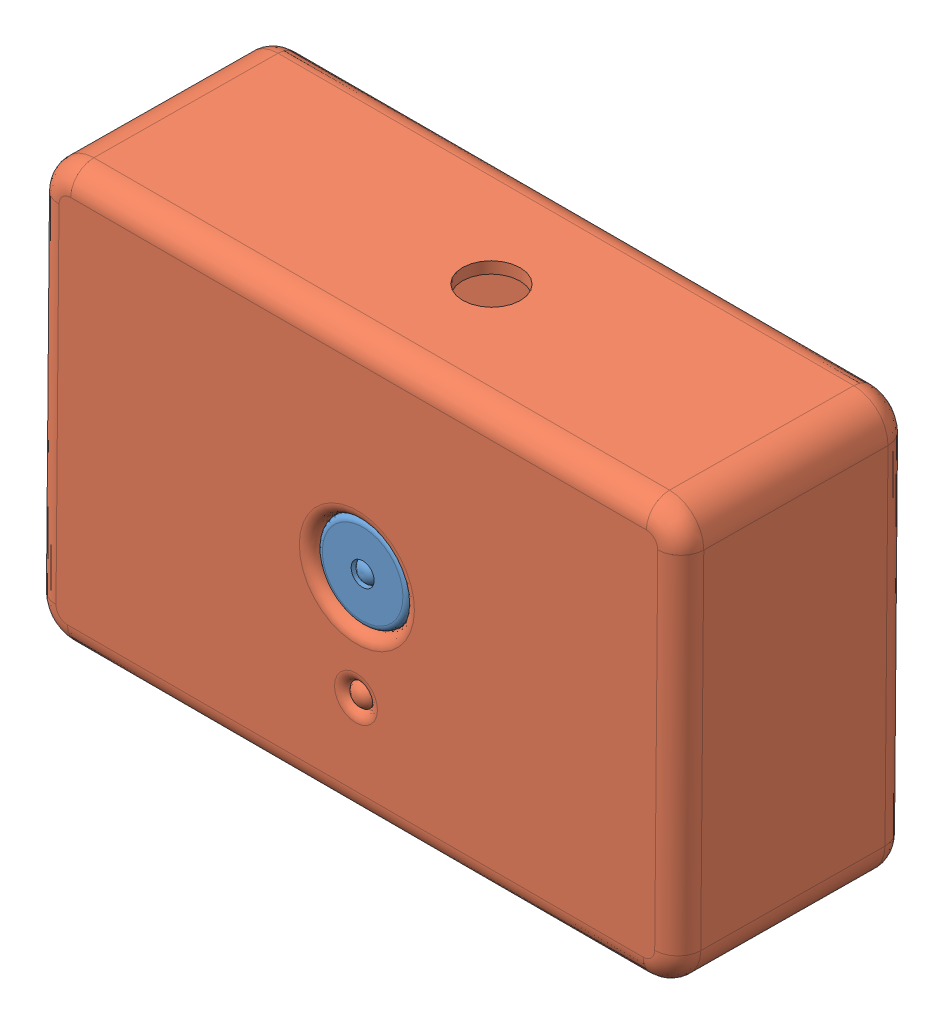
SolidWorks assembly Camara, configuration Predeterminado. Lengths in mm.
Overall size (56 36.17 20.31).
2 component instances, 2 part files, 1 mates.
Components (placement in the parent):
- Camara-1: Camara [Predeterminado] at (-38.4113 -4.107 68.8002) x (1 0 0) z (0 -0.999962 0.008727) size (30 3.56 30)
- GoProCamara-1: GoProCamara [Predeterminado] at (-38.4113 -3.0252 52.7902) x (1 0 0) z (0 0.008727 0.999962) size (56 36 20)
Mates (geometry in assembly coordinates):
- Coincidente2: coincident aligned: circle of Camara-1; circle of GoProCamara-1
